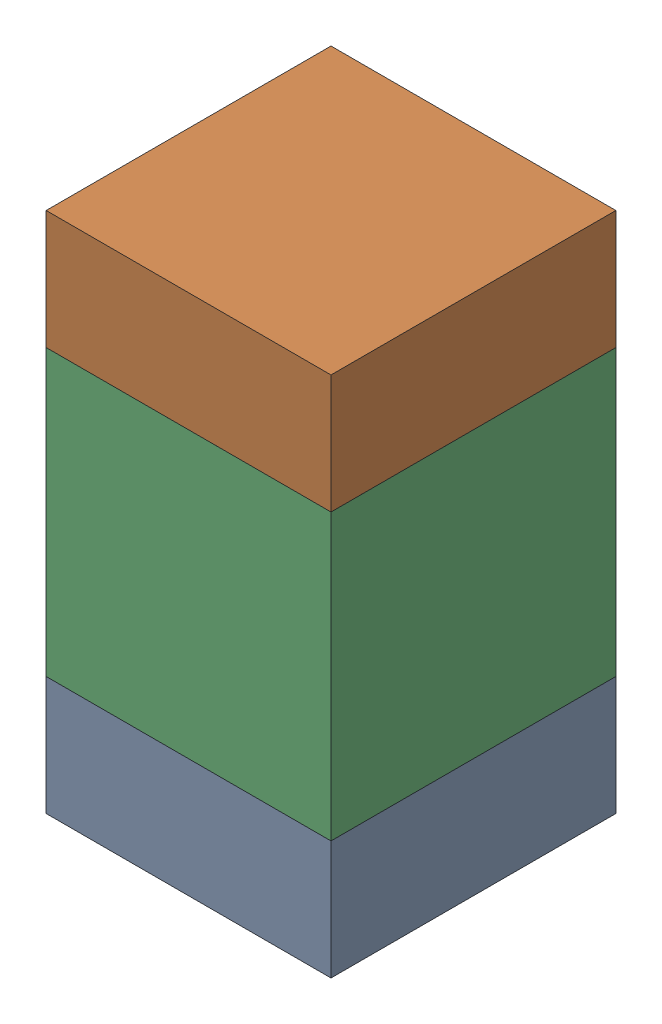
SolidWorks assembly C103_1PCB, configuration Default. Lengths in mm.
Overall size (0.6 1.1 0.6).
6 component instances, 2 part files, 0 mates.
Components (placement in the parent):
- 854785296-1: 854785296 [Default] at (104.5 105.475 0) size (0.6 0.25 0.6)
  - Extruded_10-1: Extruded_10 [Default] at origin size (0.6 0.25 0.6)
- 854785296-2: 854785296 [Default] at (104.5 106.325 0) size (0.6 0.25 0.6)
  - Extruded_10-1: Extruded_10 [Default] at origin size (0.6 0.25 0.6)
- 761606048-1: 761606048 [Default] at (104.5 105.9 0) size (0.6 0.6 0.6)
  - Extruded_9-1: Extruded_9 [Default] at origin size (0.6 0.6 0.6)
